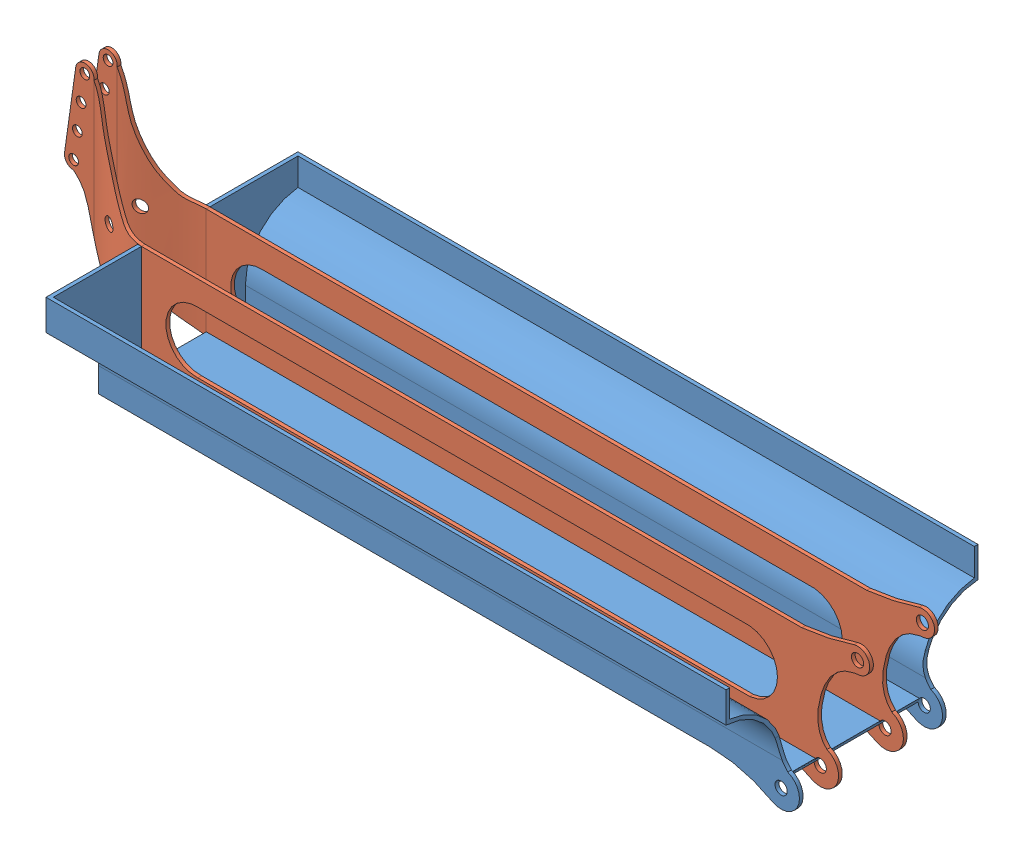
SolidWorks assembly Assem2, configuration Default. Lengths in mm.
Overall size (675.42 194.96 206).
2 component instances, 2 part files, 3 mates.
Components (placement in the parent):
- CHASSI 2 CNC-1: CHASSI 2 CNC [Default] at (-146.4255 510.6577 372.9399) size (573 105 206)
- CHASSI CNC-1: CHASSI CNC [Default] at (108.6927 345.1059 447.9399) size (675.42 194.96 73.8)
Mates (geometry in assembly coordinates):
- Concentric1: concentric aligned: cylinder of CHASSI 2 CNC-1 through (441.8564 242.1764 578.9399) axis (0 0 -1) radius 5; cylinder of CHASSI CNC-1 through (441.8564 242.1764 503.9399) axis (0 0 -1) radius 5
- Coincident1: coincident anti-aligned: plane of CHASSI 2 CNC-1 through (-116.1436 332.1764 503.9399) normal (0 0 -1); plane of CHASSI CNC-1 through (-152.4557 362.6917 503.9399) normal (0 0 1)
- Coincident2: coincident aligned: plane of CHASSI 2 CNC-1 through (439.8175 332.1764 578.9399) normal (0 1 0); plane of CHASSI CNC-1 through (384.1934 332.1764 503.9399) normal (0 1 0)
